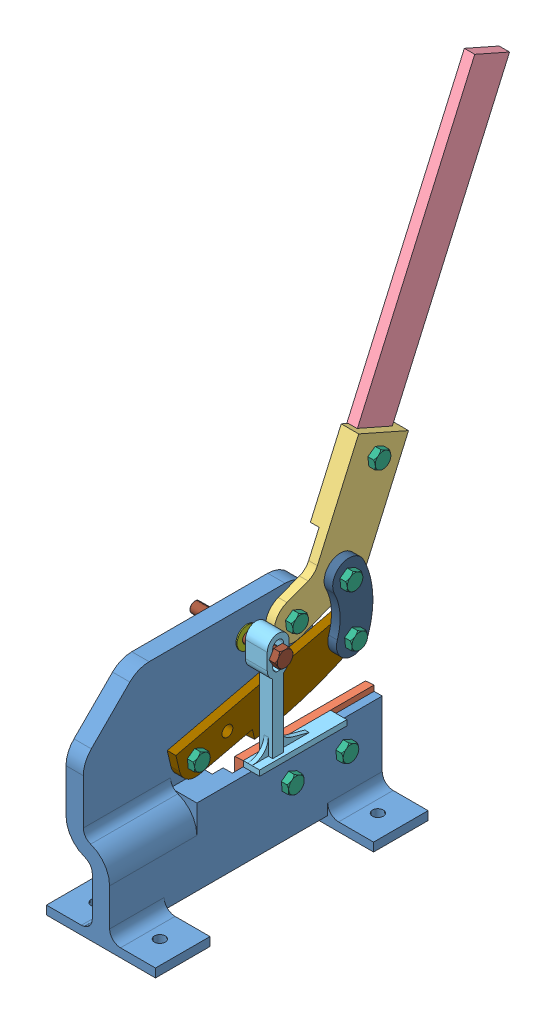
SolidWorks assembly Final Assembly Mannual Shearing Machine, configuration Default. Lengths in mm.
Overall size (113.7 520.99 390.91).
23 component instances, 11 part files, 46 mates.
Components (placement in the parent):
- Body-1: Body [Default] at (52.3495 125.3325 64.1908) size (100 187.94 250)
- Lower Blade-1: Lower Blade [Default] at (84.9105 107.8325 124.1908) x (0 0 1) z (0 -1 0) size (120 7.94 45)
- Handle Support-1: Handle Support [Default] at (68.2245 226.5716 87.223) x (0 0.914632 -0.404288) z (0 -0.404288 -0.914632) size (149.82 16 74.82)
- Handle-1: Handle [Default] at (68.2245 568.3867 -44.7745) x (0 0.914632 -0.404288) z (0 0.404288 0.914632) size (300 9.53 34.92)
- Stand-1: Stand [Default] at (84.9105 217.3325 164.1908) x (0 0 -1) z (0 -1 0) size (80 23 102)
- Bolt 3-8 inch-1: Bolt 3-8 inch [Default] at (92.3495 100.3325 149.1908) x (0 0.808543 0.588437) z (0 0.588437 -0.808543) size (14.3 26.67 18.16)
- Bolt 3-8 inch-2: Bolt 3-8 inch [Default] at (76.2245 302.486 53.6671) x (0 0.808543 0.588437) z (0 0.588437 -0.808543) size (14.3 26.67 18.16)
- Bolt 3-8 inch-3: Bolt 3-8 inch [Default] at (92.3495 100.3325 99.1908) x (0 0.808543 0.588437) z (0 0.588437 -0.808543) size (14.3 26.67 18.16)
- Bolt 3-8 inch-6: Bolt 3-8 inch [Default] at (76.2245 210.3325 129.1908) x (0 0.808543 0.588437) z (0 0.588437 -0.808543) size (14.3 26.67 18.16)
- Washer-1: Washer [Default] at (69.2245 210.3325 164.1908) x (0 1 0) z (0 0 1) size (20 1 20)
- Nut-1: Nut [Default] at (76.973 100.3325 99.1908) x (0 1 0) z (0 0 1) size (14.3 6.35 18.16)
- Nut-5: Nut [Default] at (68.2245 177.3662 82.9049) x (0 1 0) z (0 0 1) size (14.3 6.35 18.16)
- Nut-6: Nut [Default] at (68.2245 226.5716 87.223) x (0 1 0) z (0 0 1) size (14.3 6.35 18.16)
- Nut-7: Nut [Default] at (52.3495 302.486 53.6671) x (0 -1 0) z (0 0 1) size (14.3 6.35 18.16)
- Nut-8: Nut [Default] at (45.9995 210.3325 164.1908) x (0 -1 0) z (0 0 1) size (14.3 6.35 18.16)
- Nut-9: Nut [Default] at (45.9995 145.3325 219.1908) x (0 -1 0) z (0 0 1) size (14.3 6.35 18.16)
- Nut-10: Nut [Default] at (70.623 100.3325 149.1908) x (0 -1 0) z (0 0 1) size (14.3 6.35 18.16)
- Upper blade-2: Upper blade [Default] at (68.2245 195.4004 71.735) x (0 0.228812 -0.973471) z (0 -0.973471 -0.228812) size (170 7.94 41)
- Support-2: Support [Default] at (76.162 197.9898 144.5463) x (0 -0.894925 -0.446216) z (0 -0.446216 0.894925) size (75.96 7.94 49.04)
- Bolt 3-8 inch-10: Bolt 3-8 inch [Default] at (84.0995 177.3662 82.9049) x (0 0.808543 0.588437) z (0 0.588437 -0.808543) size (14.3 26.67 18.16)
- Bolt 3-8 inch-11: Bolt 3-8 inch [Default] at (84.0995 226.5716 87.223) x (0 0.808543 0.588437) z (0 0.588437 -0.808543) size (14.3 26.67 18.16)
- Bolt 3-8 inch-15: Bolt 3-8 inch [Default] at (76.162 145.3325 219.1908) x (0 0.808543 0.588437) z (0 0.588437 -0.808543) size (14.3 26.67 18.16)
- Bolt 3-8 inch - Copy-1: Bolt 3-8 inch - Copy [Default] at (96.9105 210.3325 164.1908) x (0 -1 0) z (0 0 1) size (14.3 82.55 18.16)
Mates (geometry in assembly coordinates):
- Coincident2: coincident anti-aligned: plane of Body-1 through (84.9105 125.3325 194.1908) normal (-1 0 0); plane of Lower Blade-1 through (84.9105 107.8325 124.1908) normal (1 0 0)
- Coincident3: coincident anti-aligned: circle of Body-1; circle of Lower Blade-1
- Coincident12: coincident anti-aligned: circle of Body-1; circle of Handle Support-1
- Coincident16: coincident anti-aligned: plane of Handle Support-1 through (68.2245 210.3325 129.1908) normal (-1 0 0); plane of Handle-1 through (68.2245 568.3867 -44.7745) normal (1 0 0)
- Concentric2: concentric anti-aligned: cylinder of Handle Support-1 through (76.2245 302.486 53.6671) axis (-1 0 0) radius 5; cylinder of Handle-1 through (58.6995 302.486 53.6671) axis (1 0 0) radius 5
- Parallel1: parallel anti-aligned: plane of Handle Support-1 through (60.2245 325.3119 63.2576) normal (0 -0.404288 -0.914632); plane of Handle-1 through (58.6995 568.3867 -44.7745) normal (0 0.404288 0.914632)
- Coincident19: coincident anti-aligned: plane of Handle Support-1 through (76.2245 210.3325 129.1908) normal (1 0 0); plane of Bolt 3-8 inch-2 through (76.2245 302.486 53.6671) normal (-1 0 0)
- Concentric5: concentric anti-aligned: cylinder of Handle Support-1 through (76.2245 302.486 53.6671) axis (-1 0 0) radius 5; cylinder of Bolt 3-8 inch-2 through (55.9045 302.486 53.6671) axis (1 0 0) radius 4.7625
- Coincident20: coincident anti-aligned: plane of Body-1 through (92.3495 125.3325 314.1908) normal (1 0 0); plane of Bolt 3-8 inch-3 through (92.3495 100.3325 99.1908) normal (-1 0 0)
- Concentric6: concentric aligned: cylinder of Body-1 through (34.412 100.3325 99.1908) axis (1 0 0) radius 5; cylinder of Bolt 3-8 inch-3 through (72.0295 100.3325 99.1908) axis (1 0 0) radius 4.7625
- Coincident21: coincident anti-aligned: plane of Body-1 through (92.3495 125.3325 314.1908) normal (1 0 0); plane of Bolt 3-8 inch-1 through (92.3495 100.3325 149.1908) normal (-1 0 0)
- Concentric7: concentric aligned: cylinder of Body-1 through (34.412 100.3325 149.1908) axis (1 0 0) radius 5; cylinder of Bolt 3-8 inch-1 through (72.0295 100.3325 149.1908) axis (1 0 0) radius 4.7625
- Coincident23: coincident anti-aligned: plane of Handle Support-1 through (76.2245 210.3325 129.1908) normal (1 0 0); plane of Bolt 3-8 inch-6 through (76.2245 210.3325 129.1908) normal (-1 0 0)
- Concentric10: concentric aligned: circle of Handle Support-1; cylinder of Bolt 3-8 inch-6 through (55.9045 210.3325 129.1908) axis (1 0 0) radius 4.7625
- Coincident27: coincident anti-aligned: plane of Body-1 through (68.2245 235.3325 314.1908) normal (1 0 0); plane of Washer-1 through (68.2245 210.3325 164.1908) normal (-1 0 0)
- Coincident28: coincident anti-aligned: cylinder of Body-1 through (34.412 210.3325 164.1908) axis (1 0 0) radius 5; circle of Washer-1
- Coincident30: coincident anti-aligned: plane of Body-1 through (52.3495 125.3325 204.1908) normal (0 1 0); plane of Stand-1 through (96.9105 125.3325 184.1908) normal (0 -1 0)
- Coincident32: coincident anti-aligned: plane of Lower Blade-1 through (84.9105 107.8325 124.1908) normal (1 0 0); plane of Stand-1 through (84.9105 217.3325 164.1908) normal (-1 0 0)
- Parallel2: parallel aligned: plane of Lower Blade-1 through (76.973 85.3325 184.1908) normal (0 0 1); plane of Stand-1 through (96.9105 125.3325 184.1908) normal (0 0 1)
- Concentric18: concentric anti-aligned: cylinder of Bolt 3-8 inch-3 through (72.0295 100.3325 99.1908) axis (1 0 0) radius 4.7625; cylinder of Nut-1 through (76.973 100.3325 99.1908) axis (-1 0 0) radius 4.7625
- Coincident34: coincident anti-aligned: plane of Lower Blade-1 through (76.973 107.8325 124.1908) normal (-1 0 0); plane of Nut-1 through (76.973 100.3325 99.1908) normal (1 0 0)
- Coincident35: coincident anti-aligned: plane of Lower Blade-1 through (76.973 107.8325 124.1908) normal (-1 0 0); plane of Nut-10 through (76.973 100.3325 149.1908) normal (1 0 0)
- Concentric19: concentric aligned: cylinder of Bolt 3-8 inch-1 through (72.0295 100.3325 149.1908) axis (1 0 0) radius 4.7625; cylinder of Nut-10 through (70.623 100.3325 149.1908) axis (1 0 0) radius 4.7625
- Coincident36: coincident anti-aligned: plane of Body-1 through (52.3495 125.3325 314.1908) normal (-1 0 0); plane of Nut-9 through (52.3495 145.3325 219.1908) normal (1 0 0)
- Coincident38: coincident anti-aligned: plane of Body-1 through (68.2245 235.3325 314.1908) normal (1 0 0); plane of Upper blade-2 through (68.2245 429.108 209.361) normal (-1 0 0)
- Coincident39: coincident aligned: cylinder of Body-1 through (34.412 145.3325 219.1908) axis (1 0 0) radius 5; circle of Upper blade-2
- Coincident40: coincident anti-aligned: circle of Upper blade-2; cylinder of Support-2 through (84.0995 177.3662 82.9049) axis (-1 0 0) radius 5
- Coincident41: coincident anti-aligned: plane of Upper blade-2 through (76.162 429.108 209.361) normal (1 0 0); plane of Support-2 through (76.162 187.678 113.7256) normal (-1 0 0)
- Concentric21: concentric aligned: circle of Handle Support-1; circle of Support-2
- Coincident43: coincident aligned: plane of Lower Blade-1 through (76.973 85.3325 184.1908) normal (0 0 1); plane of Stand-1 through (96.9105 125.3325 184.1908) normal (0 0 1)
- Coincident45: coincident anti-aligned: plane of Upper blade-2 through (76.162 429.108 209.361) normal (1 0 0); plane of Bolt 3-8 inch-15 through (76.162 145.3325 219.1908) normal (-1 0 0)
- Concentric22: concentric anti-aligned: cylinder of Upper blade-2 through (76.162 145.3325 219.1908) axis (-1 0 0) radius 5; cylinder of Bolt 3-8 inch-15 through (55.842 145.3325 219.1908) axis (1 0 0) radius 4.7625
- Coincident46: coincident anti-aligned: plane of Support-2 through (84.0995 187.678 113.7256) normal (1 0 0); plane of Bolt 3-8 inch-10 through (84.0995 177.3662 82.9049) normal (-1 0 0)
- Concentric23: concentric anti-aligned: cylinder of Support-2 through (84.0995 177.3662 82.9049) axis (-1 0 0) radius 5; cylinder of Bolt 3-8 inch-10 through (63.7795 177.3662 82.9049) axis (1 0 0) radius 4.7625
- Coincident47: coincident anti-aligned: plane of Support-2 through (84.0995 187.678 113.7256) normal (1 0 0); plane of Bolt 3-8 inch-11 through (84.0995 226.5716 87.223) normal (-1 0 0)
- Concentric24: concentric anti-aligned: cylinder of Support-2 through (84.0995 226.5716 87.223) axis (-1 0 0) radius 5; cylinder of Bolt 3-8 inch-11 through (63.7795 226.5716 87.223) axis (1 0 0) radius 4.7625
- Coincident48: coincident anti-aligned: plane of Handle-1 through (58.6995 568.3867 -44.7745) normal (-1 0 0); plane of Nut-7 through (58.6995 302.486 53.6671) normal (1 0 0)
- Concentric25: concentric aligned: cylinder of Bolt 3-8 inch-2 through (55.9045 302.486 53.6671) axis (1 0 0) radius 4.7625; cylinder of Nut-7 through (52.3495 302.486 53.6671) axis (1 0 0) radius 4.7625
- Concentric26: concentric anti-aligned: cylinder of Nut-6 through (68.2245 226.5716 87.223) axis (-1 0 0) radius 4.7625; cylinder of Bolt 3-8 inch-11 through (63.7795 226.5716 87.223) axis (1 0 0) radius 4.7625
- Coincident50: coincident anti-aligned: plane of Handle Support-1 through (68.2245 210.3325 129.1908) normal (-1 0 0); plane of Nut-6 through (68.2245 226.5716 87.223) normal (1 0 0)
- Concentric27: concentric anti-aligned: cylinder of Nut-5 through (68.2245 177.3662 82.9049) axis (-1 0 0) radius 4.7625; cylinder of Bolt 3-8 inch-10 through (63.7795 177.3662 82.9049) axis (1 0 0) radius 4.7625
- Coincident51: coincident anti-aligned: plane of Nut-5 through (68.2245 177.3662 82.9049) normal (1 0 0); plane of Upper blade-2 through (68.2245 429.108 209.361) normal (-1 0 0)
- Concentric28: concentric aligned: cylinder of Body-1 through (34.412 210.3325 164.1908) axis (1 0 0) radius 5; cylinder of Bolt 3-8 inch - Copy-1 through (20.7105 210.3325 164.1908) axis (1 0 0) radius 4.7625
- Coincident52: coincident anti-aligned: plane of Stand-1 through (96.9105 217.3325 164.1908) normal (1 0 0); plane of Bolt 3-8 inch - Copy-1 through (96.9105 210.3325 164.1908) normal (-1 0 0)
- Coincident53: coincident anti-aligned: plane of Body-1 through (52.3495 125.3325 314.1908) normal (-1 0 0); plane of Nut-8 through (52.3495 210.3325 164.1908) normal (1 0 0)
- Concentric29: concentric aligned: cylinder of Nut-8 through (45.9995 210.3325 164.1908) axis (1 0 0) radius 4.7625; cylinder of Bolt 3-8 inch - Copy-1 through (20.7105 210.3325 164.1908) axis (1 0 0) radius 4.7625
